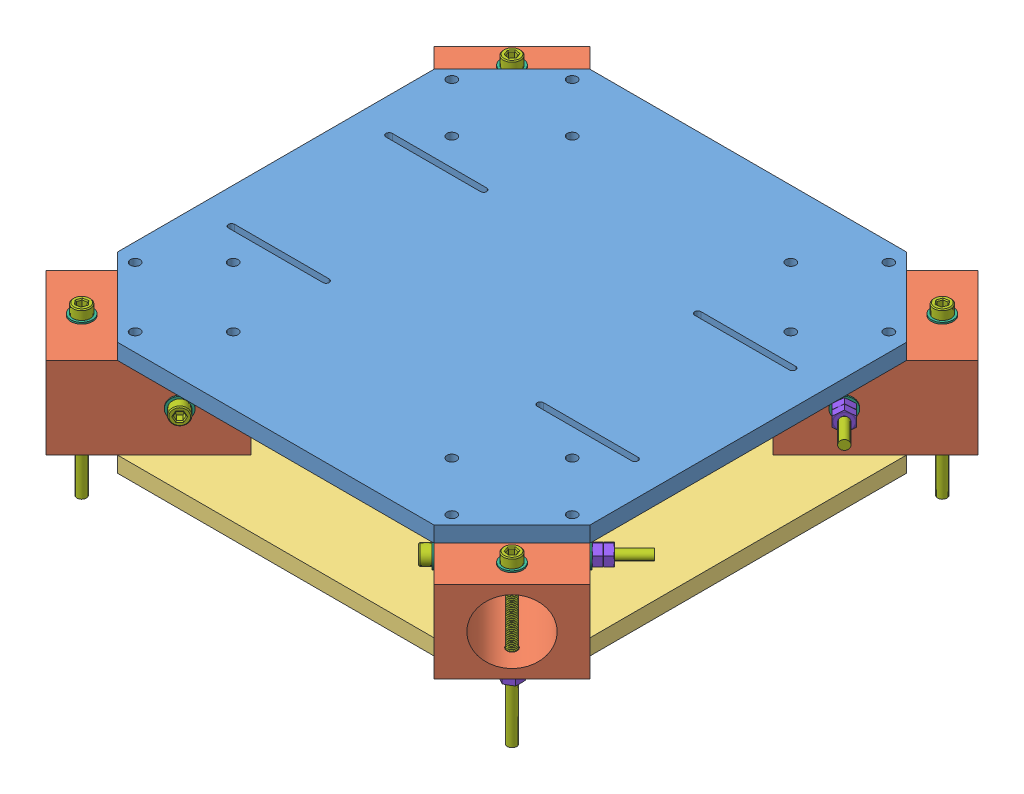
SolidWorks assembly base plate, configuration Default. Lengths in mm.
Overall size (172.63 54.5 172.63).
52 component instances, 8 part files, 27 mates.
Components (placement in the parent):
- battery plate-1: battery plate [Default] at (40.4704 62.5194 68.0793) size (150 5 150)
- spar clamp-1: spar clamp [Default] at (98.1463 47.0194 10.4034) x (0.707107 0 0.707107) z (-0.707107 0 0.707107) size (35 26 46)
- payload plate-1: payload plate [Default] at (40.4704 31.5194 68.0793) size (150 5 150)
- gimbal mount-1: gimbal mount [Default] at (99.2818 49.667 76.2539) x (0 0 -1) z (-1 0 0) size (51.5 21 51.5)
  - gimbal plate-1: gimbal plate [Default] at (8.1746 31.3476 58.8114) size (50 3 50)
  - gimbal damper-1: gimbal damper [Default] at (-8.8254 24.2476 41.8114) size (17.5 21 17.5)
  - gimbal damper-2: gimbal damper [Default] at (-8.8254 24.2476 75.8114) size (17.5 21 17.5)
  - gimbal damper-3: gimbal damper [Default] at (25.1746 24.2476 41.8114) x (-1 0 0) z (0 0 -1) size (17.5 21 17.5)
  - gimbal damper-4: gimbal damper [Default] at (25.1746 24.2476 75.8114) x (-1 0 0) z (0 0 -1) size (17.5 21 17.5)
- 9430100-1: 9430100 [Default] at (105.9245 47.0194 28.0811) x (0.5 0.707107 -0.5) z (-0.5 0.707107 0.5) size (6.9 0.5 6.9)
- 9430100-2: 9430100 [Default] at (80.4686 47.0194 2.6252) x (0.5 -0.707107 -0.5) z (-0.5 -0.707107 0.5) size (6.9 0.5 6.9)
- M3x50-1: M3x50 [Default] at (78.3473 47.0194 0.5039) x (0.707107 0 0.707107) z (-0.707107 0 0.707107) size (53 5.5 5.5)
- M3 Nut-1: M3 Nut [Default] at (108.7529 47.0194 30.9095) x (0.707107 0 -0.707107) z (0.707107 0 0.707107) size (5.43 6.27 2.71)
- M3 Nut-2: M3 Nut [Default] at (110.5207 47.0194 32.6773) x (0.707107 0 -0.707107) z (0.707107 0 0.707107) size (5.43 6.27 2.71)
- M3x50-5: M3x50 [Default] at (108.7529 63.5194 -0.2032) x (0 -1 0) z (0.9845 0 -0.175385) size (53 5.5 5.5)
- 9430100-9: 9430100 [Default] at (108.7529 60.0194 -0.2032) size (6.9 0.5 6.9)
- 9430100-10: 9430100 [Default] at (108.7529 33.5194 -0.2032) size (6.9 0.5 6.9)
- M3 Nut-9: M3 Nut [Default] at (108.7529 29.5194 -0.2032) x (1 0 0) z (0 -1 0) size (5.43 6.27 2.71)
- M3 Nut-10: M3 Nut [Default] at (108.7529 32.5194 -0.2032) x (1 0 0) z (0 1 0) size (5.43 6.27 2.71)
- M3x50-6: M3x50 [Default] at (78.3473 47.0194 135.6547) x (0.707107 0 -0.707107) z (-0.707107 0 -0.707107) size (53 5.5 5.5)
- M3 Nut-11: M3 Nut [Default] at (106.6158 47.0194 107.3861) x (-0.707107 0 -0.707107) z (-0.707107 0 0.707107) size (5.43 6.27 2.71)
- M3 Nut-12: M3 Nut [Default] at (104.8481 47.0194 109.1539) x (-0.707107 0 -0.707107) z (-0.707107 0 0.707107) size (5.43 6.27 2.71)
- 9430100-11: 9430100 [Default] at (105.9245 47.0194 108.0775) x (0.5 0.707107 0.5) z (0.5 -0.707107 0.5) size (6.9 0.5 6.9)
- M3x50-7: M3x50 [Default] at (108.7529 63.5194 136.3618) x (0 -1 0) z (0.9845 0 0.175385) size (53 5.5 5.5)
- 9430100-12: 9430100 [Default] at (108.7529 60.0194 136.3618) size (6.9 0.5 6.9)
- M3 Nut-13: M3 Nut [Default] at (108.7529 35.0416 136.3618) x (-1 0 0) z (0 1 0) size (5.43 6.27 2.71)
- M3 Nut-14: M3 Nut [Default] at (108.7529 26.9971 136.3618) x (1 0 0) z (0 -1 0) size (5.43 6.27 2.71)
- spar clamp-2: spar clamp [Default] at (98.1463 47.0194 125.7552) x (-0.707107 0 0.707107) z (-0.707107 0 -0.707107) size (35 26 46)
- 9430100-13: 9430100 [Default] at (108.7529 33.5194 136.3618) size (6.9 0.5 6.9)
- 9430100-14: 9430100 [Default] at (80.4686 47.0194 133.5333) x (0.5 -0.707107 0.5) z (0.5 0.707107 0.5) size (6.9 0.5 6.9)
- M3x50-8: M3x50 [Default] at (2.5935 47.0194 135.6547) x (-0.707107 0 -0.707107) z (0.707107 0 -0.707107) size (53 5.5 5.5)
- 9430100-15: 9430100 [Default] at (0.4722 47.0194 133.5333) x (-0.5 -0.707107 0.5) z (0.5 -0.707107 -0.5) size (6.9 0.5 6.9)
- spar clamp-3: spar clamp [Default] at (-17.2055 47.0194 125.7552) x (-0.707107 0 -0.707107) z (0.707107 0 -0.707107) size (35 26 46)
- M3x50-9: M3x50 [Default] at (-27.8121 63.5194 136.3618) x (0 -1 0) z (-0.9845 0 0.175385) size (53 5.5 5.5)
- 9430100-16: 9430100 [Default] at (-27.8121 60.0194 136.3618) x (-1 0 0) z (0 0 -1) size (6.9 0.5 6.9)
- 9430100-17: 9430100 [Default] at (-27.8121 33.5194 136.3618) x (-1 0 0) z (0 0 -1) size (6.9 0.5 6.9)
- M3 Nut-15: M3 Nut [Default] at (-27.8121 29.5194 136.3618) x (1 0 0) z (0 -1 0) size (5.43 6.27 2.71)
- M3 Nut-16: M3 Nut [Default] at (-27.8121 32.5194 136.3618) x (-1 0 0) z (0 1 0) size (5.43 6.27 2.71)
- 9430100-18: 9430100 [Default] at (-24.9837 47.0194 108.0775) x (-0.5 0.707107 0.5) z (0.5 0.707107 -0.5) size (6.9 0.5 6.9)
- M3 Nut-17: M3 Nut [Default] at (-27.8121 47.0194 105.2491) x (-0.707107 0 0.707107) z (-0.707107 0 -0.707107) size (5.43 6.27 2.71)
- M3 Nut-18: M3 Nut [Default] at (-29.5799 47.0194 103.4813) x (-0.707107 0 0.707107) z (-0.707107 0 -0.707107) size (5.43 6.27 2.71)
- M3x50-10: M3x50 [Default] at (2.5935 47.0194 0.5039) x (-0.707107 0 0.707107) z (0.707107 0 0.707107) size (53 5.5 5.5)
- M3 Nut-19: M3 Nut [Default] at (-25.675 47.0194 28.7724) x (0.707107 0 0.707107) z (0.707107 0 -0.707107) size (5.43 6.27 2.71)
- M3 Nut-20: M3 Nut [Default] at (-23.9073 47.0194 27.0047) x (0.707107 0 0.707107) z (0.707107 0 -0.707107) size (5.43 6.27 2.71)
- 9430100-19: 9430100 [Default] at (-24.9837 47.0194 28.0811) x (-0.5 0.707107 -0.5) z (-0.5 -0.707107 -0.5) size (6.9 0.5 6.9)
- spar clamp-4: spar clamp [Default] at (-17.2055 47.0194 10.4034) x (0.707107 0 -0.707107) z (0.707107 0 0.707107) size (35 26 46)
- 9430100-20: 9430100 [Default] at (-27.8121 33.5194 -0.2032) x (-1 0 0) z (0 0 -1) size (6.9 0.5 6.9)
- M3 Nut-21: M3 Nut [Default] at (-27.8121 35.0416 -0.2032) x (-1 0 0) z (0 1 0) size (5.43 6.27 2.71)
- M3 Nut-22: M3 Nut [Default] at (-27.8121 26.9971 -0.2032) x (-1 0 0) z (0 -1 0) size (5.43 6.27 2.71)
- M3x50-11: M3x50 [Default] at (-27.8121 63.5194 -0.2032) x (0 -1 0) z (-0.9845 0 -0.175385) size (53 5.5 5.5)
- 9430100-21: 9430100 [Default] at (-27.8121 60.0194 -0.2032) x (-1 0 0) z (0 0 -1) size (6.9 0.5 6.9)
- 9430100-22: 9430100 [Default] at (0.4722 47.0194 2.6252) x (-0.5 -0.707107 -0.5) z (-0.5 0.707107 -0.5) size (6.9 0.5 6.9)
Mates (geometry in assembly coordinates):
- Coincident1: coincident anti-aligned: plane of battery plate-1 through (40.4704 60.0194 68.0793) normal (0 -1 0); plane of spar clamp-1 through (98.1463 60.0194 10.4034) normal (0 1 0)
- Coincident2: coincident anti-aligned: plane of spar clamp-1 through (98.1463 34.0194 10.4034) normal (0 -1 0); plane of payload plate-1 through (40.4704 34.0194 68.0793) normal (0 1 0)
- Coincident3: coincident anti-aligned: plane of payload plate-1 through (40.4704 34.0194 68.0793) normal (0 1 0); plane of gimbal mount-1/gimbal damper-3 through (57.4704 34.0194 55.5793) normal (0 -1 0)
- Concentric5: concentric aligned: cylinder of payload plate-1 through (57.4704 -5.9663 85.0793) axis (0 1 0) radius 5.25; cylinder of gimbal mount-1/gimbal damper-1 through (57.4704 17.9194 85.0793) axis (0 1 0) radius 3.5
- Concentric6: concentric aligned: cylinder of payload plate-1 through (57.4704 -5.9663 51.0793) axis (0 1 0) radius 5.25; cylinder of gimbal mount-1/gimbal damper-3 through (57.4704 17.9194 51.0793) axis (0 1 0) radius 3.5
- Coincident4: coincident anti-aligned: plane of spar clamp-1 through (94.2572 60.0194 39.0412) normal (0.707107 0 0.707107); plane of 9430100-1 through (105.5709 47.0194 27.7275) normal (-0.707107 0 -0.707107)
- Coincident5: coincident anti-aligned: plane of spar clamp-1 through (69.5085 60.0194 14.2925) normal (-0.707107 0 -0.707107); plane of 9430100-2 through (80.8222 47.0194 2.9788) normal (0.707107 0 0.707107)
- Coincident6: coincident anti-aligned: plane of 9430100-2 through (80.4686 47.0194 2.6252) normal (-0.707107 0 -0.707107); plane of M3x50-1 through (80.4686 48.5094 2.6252) normal (0.707107 0 0.707107)
- Coincident7: coincident anti-aligned: plane of 9430100-1 through (105.9245 47.0194 28.0811) normal (0.707107 0 0.707107); plane of M3 Nut-1 through (105.9245 47.0194 28.0811) normal (-0.707107 0 -0.707107)
- Concentric10: concentric aligned: cylinder of M3x50-1 through (115.824 47.0194 37.9806) axis (-0.707107 0 -0.707107) radius 1.5; circle of M3 Nut-1
- Coincident8: coincident anti-aligned: plane of M3 Nut-1 through (107.6922 47.0194 29.8488) normal (0.707107 0 0.707107); plane of M3 Nut-2 through (107.6922 47.0194 29.8488) normal (-0.707107 0 -0.707107)
- Concentric11: concentric aligned: cylinder of M3x50-1 through (115.824 47.0194 37.9806) axis (-0.707107 0 -0.707107) radius 1.5; circle of M3 Nut-2
- Concentric12: concentric aligned: cylinder of battery plate-1 through (94.2572 55.6353 33.3844) axis (0 1 0) radius 1.55; cylinder of spar clamp-1 through (94.2572 29.3525 33.3844) axis (0 1 0) radius 1.65
- Concentric13: concentric aligned: cylinder of battery plate-1 through (109.8135 55.6353 17.828) axis (0 1 0) radius 1.55; cylinder of spar clamp-1 through (109.8135 29.3525 17.828) axis (0 1 0) radius 1.65
- Concentric14: concentric aligned: cylinder of spar clamp-1 through (108.8709 47.0194 31.0275) axis (-0.707107 0 -0.707107) radius 1.65; cylinder of 9430100-1 through (105.5709 47.0194 27.7275) axis (-0.707107 0 -0.707107) radius 1.65
- Concentric15: concentric aligned: cylinder of spar clamp-1 through (108.8709 47.0194 31.0275) axis (-0.707107 0 -0.707107) radius 1.65; cylinder of M3x50-1 through (115.824 47.0194 37.9806) axis (-0.707107 0 -0.707107) radius 1.5
- Concentric16: concentric aligned: cylinder of spar clamp-1 through (108.7529 29.3525 -0.2032) axis (0 1 0) radius 1.65; cylinder of M3x50-5 through (108.7529 10.5194 -0.2032) axis (0 1 0) radius 1.5
- Concentric18: concentric anti-aligned: cylinder of 9430100-2 through (80.4686 47.0194 2.6252) axis (0.707107 0 0.707107) radius 3.45; cylinder of M3x50-1 through (15.623 47.0194 -62.2204) axis (-0.707107 0 -0.707107) radius 2.75
- Concentric19: concentric aligned: cylinder of M3x50-5 through (108.7529 152.2249 -0.2032) axis (0 1 0) radius 2.75; cylinder of 9430100-9 through (108.7529 60.5194 -0.2032) axis (0 1 0) radius 1.65
- Coincident9: coincident anti-aligned: plane of spar clamp-1 through (98.1463 60.0194 10.4034) normal (0 1 0); plane of 9430100-9 through (108.7529 60.0194 -0.2032) normal (0 -1 0)
- Coincident10: coincident anti-aligned: plane of M3x50-5 through (108.4916 60.5194 -1.6701) normal (0 -1 0); plane of 9430100-9 through (108.7529 60.5194 -0.2032) normal (0 1 0)
- Coincident11: coincident anti-aligned: plane of spar clamp-1 through (98.1463 34.0194 10.4034) normal (0 -1 0); plane of 9430100-10 through (108.7529 34.0194 -0.2032) normal (0 1 0)
- Concentric20: concentric aligned: cylinder of M3x50-5 through (108.7529 10.5194 -0.2032) axis (0 1 0) radius 1.5; cylinder of 9430100-10 through (108.7529 34.0194 -0.2032) axis (0 1 0) radius 1.65
- Coincident12: coincident anti-aligned: plane of 9430100-10 through (108.7529 33.5194 -0.2032) normal (0 -1 0); plane of M3 Nut-9 through (108.7529 33.5194 -0.2032) normal (0 1 0)
- Concentric21: concentric aligned: cylinder of M3x50-5 through (108.7529 10.5194 -0.2032) axis (0 1 0) radius 1.5; circle of M3 Nut-9
- Coincident13: coincident anti-aligned: plane of M3 Nut-9 through (108.7529 31.0194 -0.2032) normal (0 -1 0); plane of M3 Nut-10 through (108.7529 31.0194 -0.2032) normal (0 1 0)
- Concentric22: concentric anti-aligned: cylinder of M3x50-5 through (108.7529 10.5194 -0.2032) axis (0 1 0) radius 1.5; circle of M3 Nut-10
